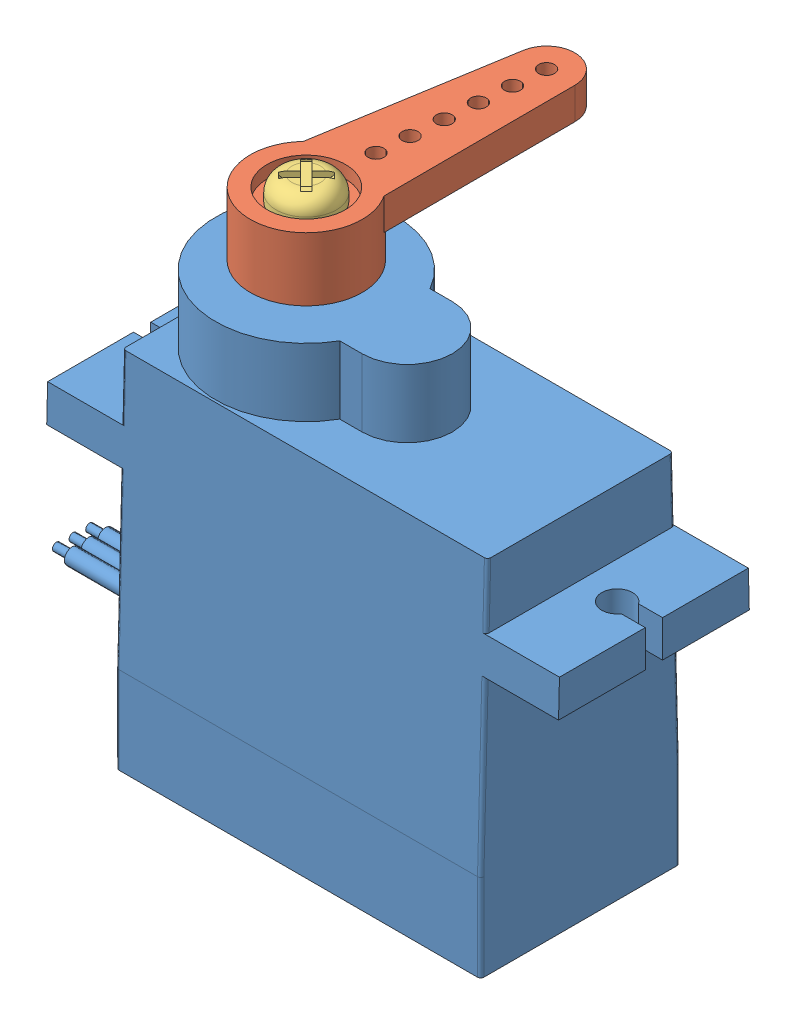
SolidWorks assembly Tower Pro 9g Micro Servo SG90, configuration Default. Lengths in mm.
Overall size (36.67 32.23 22.39).
3 component instances, 3 part files, 4 mates.
Components (placement in the parent):
- Tower Pro 9g Micro Servo SG90-1: Tower Pro 9g Micro Servo SG90 [Default] at origin size (36.67 29.95 12.59)
- SG90 plastic Horn-1: SG90 plastic Horn [Default] at (-1.405 13.16 0) x (0.080382 0 -0.996764) z (0.996764 0 0.080382) size (19.4 4 7.07)
- SM-S2309S-Screw-1: SM-S2309S-Screw [Default] at (-1.405 14.36 0) x (0.707107 0 -0.707107) z (0.707107 0 0.707107) size (3.8 6.73 3.8)
Mates (geometry in assembly coordinates):
- Coincident4: coincident anti-aligned: plane of SG90 plastic Horn-1 through (-1.2061 14.36 -2.467) normal (0 1 0); plane of SM-S2309S-Screw-1 through (-0.5741 14.36 -0.8309) normal (0 -1 0)
- Concentric1: concentric aligned: cylinder of SG90 plastic Horn-1 through (-1.405 68.16 0) axis (0 1 0) radius 2.375; cylinder of SM-S2309S-Screw-1 through (-1.405 9.16 0) axis (0 1 0) radius 1.175
- Coincident5: coincident anti-aligned: circle of Tower Pro 9g Micro Servo SG90-1; plane of SG90 plastic Horn-1 through (-1.3049 13.61 -1.241) normal (0 -1 0)
- Concentric2: concentric aligned: cylinder of Tower Pro 9g Micro Servo SG90-1 through (-1.405 9.66 0) axis (0 1 0) radius 2.3; cylinder of SG90 plastic Horn-1 through (-1.405 68.16 0) axis (0 1 0) radius 3.535
